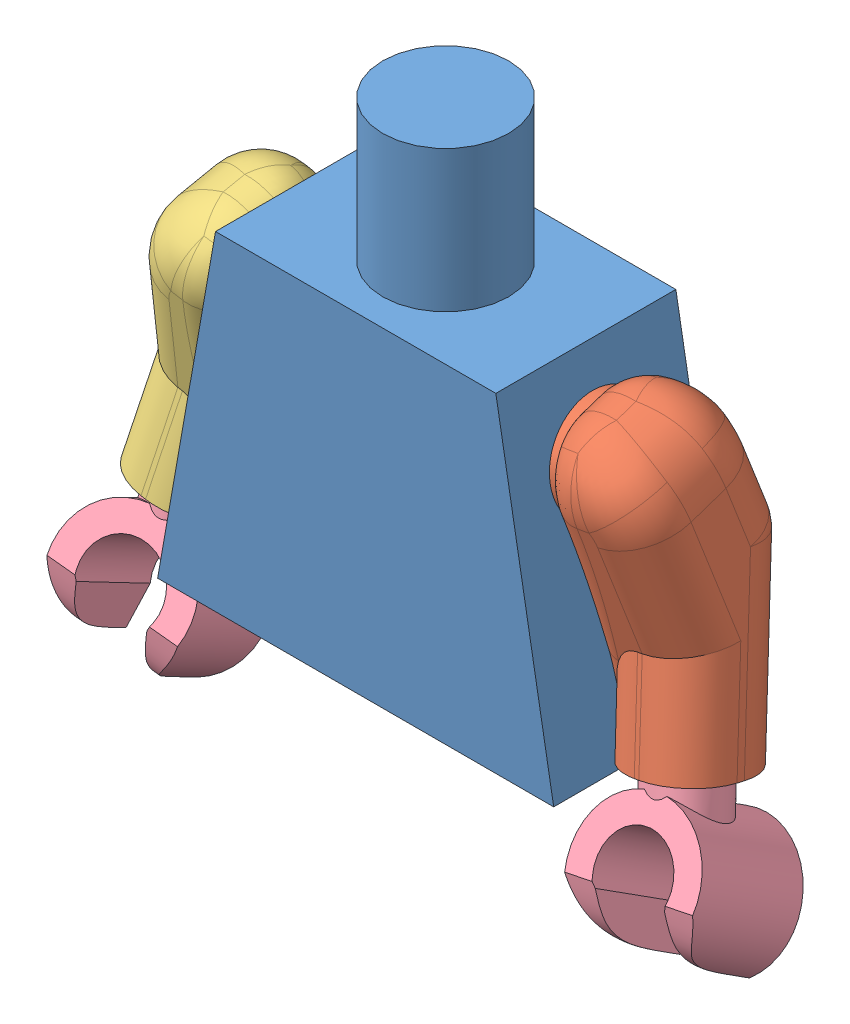
SolidWorks assembly 4288003, configuration Default. Lengths in mm.
Overall size (26.17 24.55 11.38).
5 component instances, 4 part files, 8 mates.
Components (placement in the parent):
- Base Torso-1: Base Torso [Default] at (-3.5924 8.8164 -2.0571) size (15.4 18.3 7)
- Base Arm Left-1: Base Arm Left [Default] at (3.1062 8.1133 1.3031) x (0.166786 -0.948824 -0.268169) z (0.9849 0.173127 0) size (12.12 7.19 6.37)
- Base Arm Right-1: Base Arm Right [Default] at (-18.1705 9.4967 1.3565) x (-0.167443 -0.952565 -0.254131) z (0.9849 -0.173127 0) size (12.12 7.19 6.37)
- Base Hand-1: Base Hand [Default] at (6.6274 -1.4852 0.45) x (0.164395 -0.834148 0.526471) z (-0.985421 -0.162598 0.050083) size (10.77 6.15 4.9)
- Base Hand-2: Base Hand [Default] at (-14.0754 -1.4513 0.6535) x (-0.119041 -0.834396 0.538156) z (-0.978765 0.189713 0.07764) size (10.77 6.15 4.9)
Mates (geometry in assembly coordinates):
- Concentric3: concentric anti-aligned: cylinder of Base Torso-1; cylinder of Base Arm Left-1
- Concentric4: concentric anti-aligned: cylinder of Base Torso-1; cylinder of Base Arm Right-1
- Coincident8: coincident anti-aligned: plane of Base Torso-1 through (-9.0424 15.2164 4.9429) normal (-0.9849 0.173127 0); plane of Base Arm Right-1 through (-9.3532 13.448 4.6413) normal (0.9849 -0.173127 0)
- Coincident9: coincident anti-aligned: plane of Base Torso-1 through (4.1076 2.4164 4.9429) normal (0.9849 0.173127 0); plane of Base Arm Left-1 through (2.1765 13.402 4.6663) normal (-0.9849 -0.173127 0)
- Concentric6: concentric aligned: cylinder of Base Arm Right-1; cylinder of Base Hand-2
- Concentric7: concentric aligned: cylinder of Base Arm Left-1; cylinder of Base Hand-1
- Coincident11: coincident anti-aligned: plane of Base Arm Left-1 through (7.9073 3.9046 3.5509) normal (0.16947 -0.964097 0.204443); plane of Base Hand-1 through (5.9214 3.13 1.5442) normal (-0.16947 0.964097 -0.204443)
- Coincident12: coincident anti-aligned: plane of Base Arm Right-1 through (-15.0866 3.9357 3.6765) normal (-0.168938 -0.961067 0.218657); plane of Base Hand-2 through (-13.1058 3.1324 1.6761) normal (0.168938 0.961067 -0.218657)
